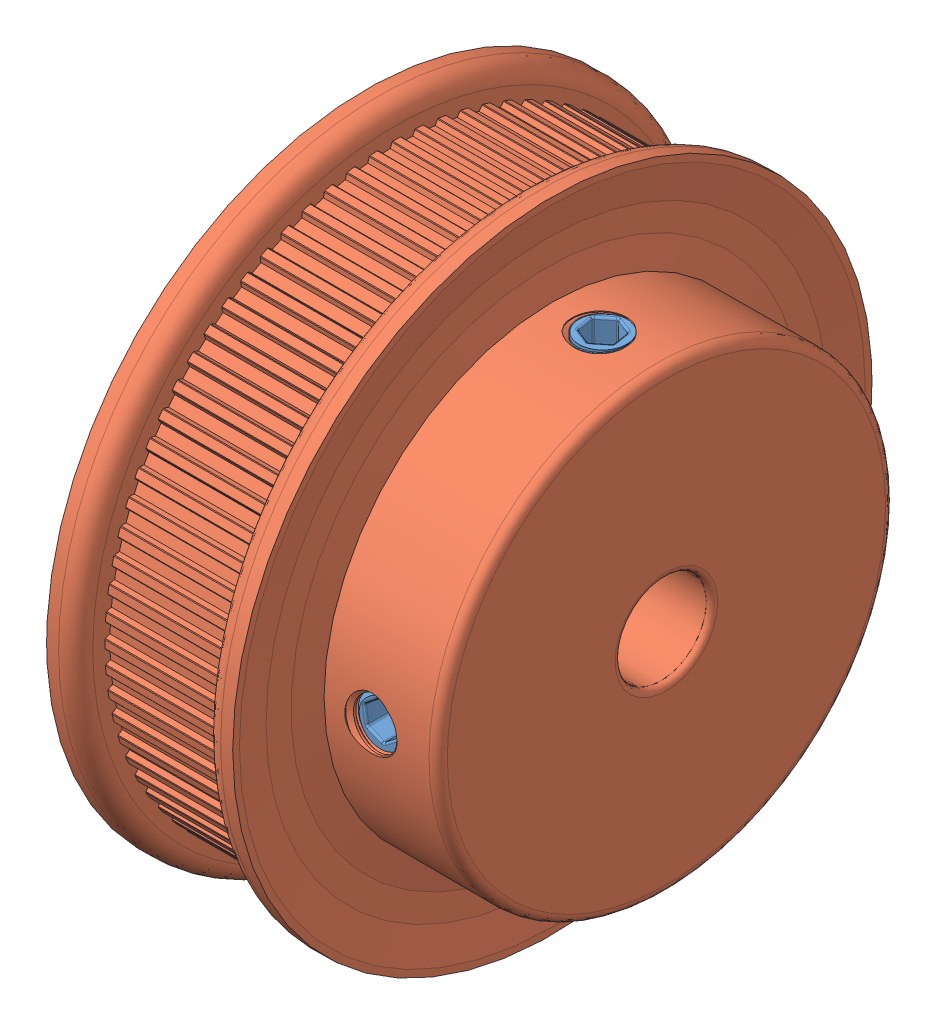
SolidWorks assembly Montagem1, configuration Valor predeterminado. Lengths in mm.
Overall size (26.3 56 56).
3 component instances, 2 part files, 0 mates.
Components (placement in the parent):
- setscrew M5-1: setscrew M5 [Valor predeterminado] at (-25.902 20.253 22.6746) x (1 0 0) z (0 -0.008727 0.999962) size (4.2 10.42 4.29)
- PULLEY MXL80 2mm-1: PULLEY MXL80 2mm [Valor predeterminado] at (-44.0836 9.9801 22.6661) size (26.3 56 56)
- setscrew M5-2: setscrew M5 [Valor predeterminado] at (-26.1675 9.946 32.0586) x (1 0 0) z (0 -1 0) size (4.2 10.42 4.29)
